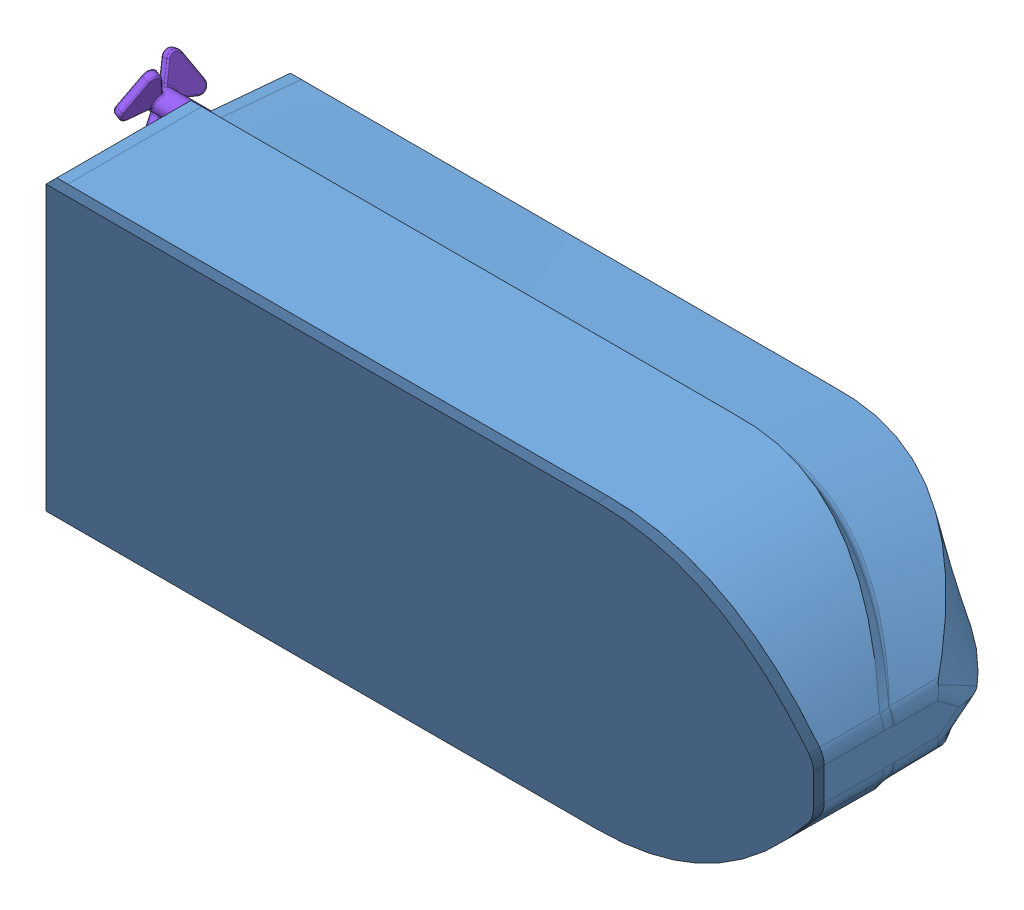
SolidWorks assembly dumb_boat, configuration Default. Lengths in mm.
Overall size (102.67 34.57 31.12).
13 component instances, 10 part files, 29 mates.
Components (placement in the parent):
- hull-1: hull [Default] x (1 0 0) z (0 0 -1) size (90.48 34.52 30)
- grommet-1: grommet [Default] at (1.2167 8.255 -12.954) size (2.46 8.33 8.33)
- grommet-2: grommet [Default] at (1.2167 -8.255 -12.954) size (2.46 8.33 8.33)
- battery_400mAh-1: battery_400mAh [Default] at (46.5002 0 -17.0979) x (-1 0 0) z (0 1 0) size (36.32 5.21 24.13)
- miniBoard-1: miniBoard [Default] at (31.9024 0 -4.4571) size (63.75 30.48 10.03)
- XBee-2: XBee [Default] at (46.1264 0 3.0039) x (0 -1 0) z (-1 0 0) size (24.5 7.64 28)
- minimotor_0615NS_sld-1: minimotor_0615NS_sld [Default] at (10.0457 8.255 -12.954) x (0 0 1) z (-1 0 0) size (5.99 5.99 18.24)
- minimotor_0615NS_sld-2: minimotor_0615NS_sld [Default] at (10.0457 -8.255 -12.954) x (0 0 1) z (-1 0 0) size (5.99 5.99 18.24)
- minimotor_gearbox_4to1-1: minimotor_gearbox_4to1 [Default] at (10.0457 8.255 -12.954) x (0 -0.383049 -0.923728) z (1 0 0) size (5.98 5.98 13.61)
- minimotor_gearbox_4to1-2: minimotor_gearbox_4to1 [Default] at (10.0457 -8.255 -12.954) x (0 -0.383049 -0.923728) z (1 0 0) size (5.98 5.98 13.61)
- propeller_LH-1: propeller_LH [Default] at (-0.7747 8.255 -12.954) x (1 0 0) z (0 0.83673 -0.547616) size (12.7 7.89 8.87)
- propeller_RH-1: propeller_RH [Default] at (-0.7747 -8.255 -12.954) size (12.7 7.89 8.87)
- cap-1: cap [Default] x (1 0 0) z (0 0 -1) size (90.17 33.95 8.29)
Mates (geometry in assembly coordinates):
- Coincident1: coincident anti-aligned: plane of hull-1 through (0 0 0) normal (0 0 -1); plane of assembly through (0 0 0) normal (0 0 1)
- Coincident2: coincident anti-aligned: plane of hull-1 through (0 0 0) normal (0 -1 0); plane of assembly through (0 0 0) normal (0 1 0)
- Coincident3: coincident aligned: plane of hull-1; plane of assembly through (0 0 0) normal (1 0 0)
- Concentric1: concentric aligned: cylinder of hull-1 through (-47.625 8.255 -12.954) axis (1 0 0) radius 3.175; cylinder of grommet-1 through (14.2135 8.255 -12.954) axis (1 0 0) radius 3.175
- Concentric2: concentric aligned: cylinder of hull-1 through (-47.625 -8.255 -12.954) axis (1 0 0) radius 3.175; cylinder of grommet-2 through (14.2135 -8.255 -12.954) axis (1 0 0) radius 3.175
- Coincident4: coincident anti-aligned: plane of hull-1 through (0.0254 0 0) normal (1 0 0); plane of grommet-2 through (0.0254 -5.08 -12.954) normal (-1 0 0)
- Coincident5: coincident anti-aligned: plane of hull-1 through (0.0254 0 0) normal (1 0 0); plane of grommet-1 through (0.0254 11.43 -12.954) normal (-1 0 0)
- Coincident9: coincident aligned: plane of battery_400mAh-1 through (46.5002 0 -17.0979) normal (0 1 0); plane of assembly through (0 0 0) normal (0 1 0)
- Coincident10: coincident aligned: plane of miniBoard-1 through (31.9024 0 -4.4571) normal (0 1 0); plane of assembly through (0 0 0) normal (0 1 0)
- Coincident11: coincident anti-aligned: plane of hull-1 through (0.0254 0 0) normal (1 0 0); plane of miniBoard-1 through (0.0254 15.24 -3.5681) normal (-1 0 0)
- Coincident12: coincident anti-aligned: plane of miniBoard-1 through (31.9024 0 1.0039) normal (0 0 1); plane of XBee-2 through (56.2333 -11.6741 1.0039) normal (0 0 -1)
- Coincident13: coincident anti-aligned: plane of XBee-2; plane of assembly through (0 0 0) normal (0 1 0)
- Distance1: distance = 14.224 mm anti-aligned: plane of XBee-2 through (46.1264 0 3.0039) normal (-1 0 0); plane of miniBoard-1 through (31.9024 0 -4.4571) normal (1 0 0)
- Coincident14: coincident anti-aligned: plane of minimotor_0615NS_sld-1 through (10.0457 8.255 -12.954) normal (-1 0 0); plane of minimotor_gearbox_4to1-1 through (10.0457 11.0177 -14.0996) normal (1 0 0)
- Concentric3: concentric aligned: cylinder of minimotor_0615NS_sld-1 through (25.4635 8.255 -12.954) axis (1 0 0) radius 2.9972; cylinder of minimotor_gearbox_4to1-1 through (24.4501 8.255 -12.954) axis (1 0 0) radius 2.9909
- Concentric4: concentric aligned: cylinder of minimotor_0615NS_sld-2 through (25.4635 -8.255 -12.954) axis (1 0 0) radius 2.9972; cylinder of minimotor_gearbox_4to1-2 through (24.4501 -8.255 -12.954) axis (1 0 0) radius 2.9909
- Coincident15: coincident anti-aligned: plane of minimotor_0615NS_sld-2 through (10.0457 -8.255 -12.954) normal (-1 0 0); plane of minimotor_gearbox_4to1-2 through (10.0457 -5.4923 -14.0996) normal (1 0 0)
- Concentric6: concentric aligned: cylinder of grommet-1 through (14.2135 8.255 -12.954) axis (1 0 0) radius 1.9844; cylinder of minimotor_0615NS_sld-1 through (25.4635 8.255 -12.954) axis (1 0 0) radius 2.9972
- Concentric7: concentric aligned: cylinder of grommet-2 through (14.2135 -8.255 -12.954) axis (1 0 0) radius 1.9844; cylinder of minimotor_0615NS_sld-2 through (25.4635 -8.255 -12.954) axis (1 0 0) radius 2.9972
- Coincident16: coincident anti-aligned: plane of hull-1 through (25.0825 0 0) normal (-1 0 0); plane of minimotor_0615NS_sld-2 through (25.0825 -6.6675 -12.954) normal (1 0 0)
- Coincident17: coincident anti-aligned: plane of hull-1 through (25.0825 0 0) normal (-1 0 0); plane of minimotor_0615NS_sld-1 through (25.0825 9.8425 -12.954) normal (1 0 0)
- Coincident18: coincident aligned: plane of hull-1 through (0 0 -5.3461) normal (0 0 -1); plane of miniBoard-1 through (31.9024 0 -5.3461) normal (0 0 -1)
- Concentric8: concentric aligned: cylinder of minimotor_gearbox_4to1-1 through (24.4501 8.255 -12.954) axis (1 0 0) radius 0.5; cylinder of propeller_LH-1 through (20.0047 8.255 -12.954) axis (1 0 0) radius 1.27
- Coincident19: coincident anti-aligned: plane of minimotor_gearbox_4to1-1 through (-0.7747 9.5454 -13.4891) normal (-1 0 0); plane of propeller_LH-1 through (-0.7747 8.255 -12.954) normal (1 0 0)
- Coincident20: coincident anti-aligned: plane of minimotor_gearbox_4to1-2 through (-0.7747 -6.9646 -13.4891) normal (-1 0 0); plane of propeller_RH-1 through (-0.7747 -8.255 -12.954) normal (1 0 0)
- Concentric9: concentric aligned: cylinder of minimotor_gearbox_4to1-2 through (24.4501 -8.255 -12.954) axis (1 0 0) radius 0.5; cylinder of propeller_RH-1 through (20.0047 -8.255 -12.954) axis (1 0 0) radius 1.27
- Coincident22: coincident anti-aligned: plane of cap-1 through (0 0 0) normal (0 -1 0); plane of assembly through (0 0 0) normal (0 1 0)
- Coincident23: coincident aligned: plane of cap-1; plane of assembly through (0 0 0) normal (1 0 0)
- Coincident24: coincident anti-aligned: plane of cap-1 through (0 0 0) normal (0 0 -1); plane of assembly through (0 0 0) normal (0 0 1)
